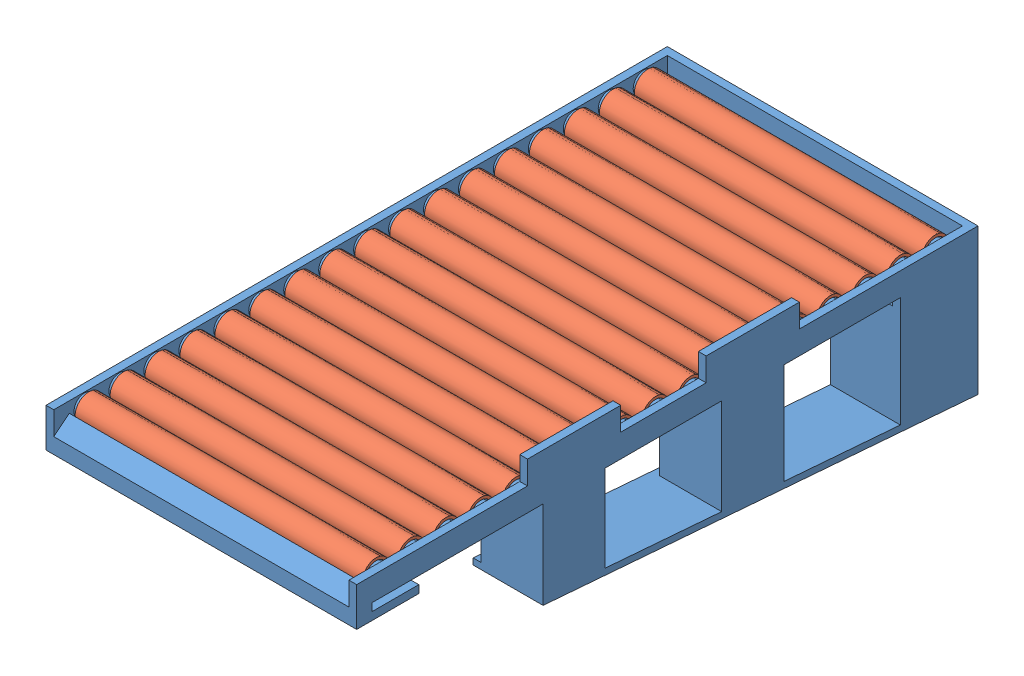
SolidWorks assembly LINE ASS, configuration Default. Lengths in mm.
Overall size (4000 2180 8000).
24 component instances, 4 part files, 54 mates.
Components (placement in the parent):
- LINE PRODUCTION-1: LINE PRODUCTION [Default] at origin size (4000 2180 8000)
- ROLLER-1: ROLLER [Default] at (0 150 3600) x (0 0.325893 0.945407) z (-1 0 0) size (350 350 3700)
- ROLLER-2: ROLLER [Default] at (0 150 3150) x (0 0 1) z (-1 0 0) size (350 350 3700)
- ROLLER-3: ROLLER [Default] at (0 150 2700) x (0 0 1) z (-1 0 0) size (350 350 3700)
- ROLLER-4: ROLLER [Default] at (0 150 2250) x (0 -0.864949 0.501859) z (-1 0 0) size (350 350 3700)
- ROLLER-5: ROLLER [Default] at (0 150 1800) x (0 0 1) z (-1 0 0) size (350 350 3700)
- ROLLER-6: ROLLER [Default] at (0 150 1350) x (0 0.030187 0.999544) z (-1 0 0) size (350 350 3700)
- ROLLER-7: ROLLER [Default] at (0 150 450) x (0 0.996582 0.082614) z (-1 0 0) size (350 350 3700)
- ROLLER-8: ROLLER [Default] at (0 150 0) x (0 0 1) z (-1 0 0) size (350 350 3700)
- ROLLER-9: ROLLER [Default] at (0 150 900) x (0 -0.361028 -0.932555) z (1 0 0) size (350 350 3700)
- ROLLER-10: ROLLER [Default] at (0 150 -450) x (0 -0.924225 -0.381849) z (1 0 0) size (350 350 3700)
- ROLLER-11: ROLLER [Default] at (0 150 -900) x (0 -0.924225 -0.381849) z (1 0 0) size (350 350 3700)
- ROLLER-13: ROLLER [Default] at (0 150 -1350) x (0 -0.924225 -0.381849) z (1 0 0) size (350 350 3700)
- ROLLER-14: ROLLER [Default] at (0 150 -1800) x (0 -0.924225 -0.381849) z (1 0 0) size (350 350 3700)
- ROLLER-15: ROLLER [Default] at (0 150 -2250) x (0 -0.924225 -0.381849) z (1 0 0) size (350 350 3700)
- ROLLER-16: ROLLER [Default] at (0 150 -2700) x (0 -0.924225 -0.381849) z (1 0 0) size (350 350 3700)
- ROLLER-17: ROLLER [Default] at (0 150 -3150) x (0 -0.650504 -0.759502) z (1 0 0) size (350 350 3700)
- ROLLER-18: ROLLER [Default] at (0 150 -3600) x (0 0.802662 -0.596435) z (1 0 0) size (350 350 3700)
- Support-1: Support [Default] at (1900 460 1466) x (0 0 1) z (-1 0 0) size (40 50 40)
- Support-2: Support [Default] at (1900 510 934) x (0 0 -1) z (-1 0 0) size (40 50 40)
- pusher-1: pusher [Default] at (1854 483.9666 1200) x (0 0 1) z (-1 0 0) size (600 100.08 85.42)
- pusher-2: pusher [Default] at (1854 477.8178 -1100) x (0 0 1) z (-1 0 0) size (600 100.08 85.42)
- Support-3: Support [Default] at (1900 471.1677 -1366) x (0 0 -1) z (-1 0 0) size (40 50 40)
- Support-4: Support [Default] at (1900 460 -834) x (0 0 1) z (-1 0 0) size (40 50 40)
Mates (geometry in assembly coordinates):
- Concentric1: concentric anti-aligned: cylinder of LINE PRODUCTION-1 through (2295.9798 150 3600) axis (-1 0 0) radius 140; cylinder of ROLLER-1 through (-1850 150 3600) axis (1 0 0) radius 141.5
- Coincident1: coincident anti-aligned: plane of ROLLER-1 through (0 150 3600) normal (-1 0 0); plane of assembly through (0 0 0) normal (1 0 0)
- Concentric3: concentric anti-aligned: cylinder of LINE PRODUCTION-1 through (2295.9798 150 3150) axis (-1 0 0) radius 140; cylinder of ROLLER-2 through (-1850 150 3150) axis (1 0 0) radius 175
- Coincident2: coincident anti-aligned: plane of ROLLER-2 through (0 150 3150) normal (-1 0 0); plane of assembly through (0 0 0) normal (1 0 0)
- Concentric4: concentric anti-aligned: cylinder of LINE PRODUCTION-1 through (2295.9798 150 2700) axis (-1 0 0) radius 140; cylinder of ROLLER-3 through (-1850 150 2700) axis (1 0 0) radius 175
- Coincident3: coincident anti-aligned: plane of ROLLER-3 through (0 150 2700) normal (-1 0 0); plane of assembly through (0 0 0) normal (1 0 0)
- Concentric5: concentric anti-aligned: cylinder of LINE PRODUCTION-1 through (2295.9798 150 2250) axis (-1 0 0) radius 140; cylinder of ROLLER-4 through (-1850 150 2250) axis (1 0 0) radius 175
- Coincident4: coincident anti-aligned: plane of ROLLER-4 through (0 150 2250) normal (-1 0 0); plane of assembly through (0 0 0) normal (1 0 0)
- Concentric6: concentric anti-aligned: cylinder of LINE PRODUCTION-1 through (2295.9798 150 1800) axis (-1 0 0) radius 140; cylinder of ROLLER-5 through (-1850 150 1800) axis (1 0 0) radius 175
- Concentric7: concentric anti-aligned: cylinder of LINE PRODUCTION-1 through (2295.9798 150 1350) axis (-1 0 0) radius 140; cylinder of ROLLER-6 through (-1850 150 1350) axis (1 0 0) radius 175
- Concentric8: concentric anti-aligned: cylinder of LINE PRODUCTION-1 through (2295.9798 150 450) axis (-1 0 0) radius 140; cylinder of ROLLER-7 through (-1850 150 450) axis (1 0 0) radius 175
- Concentric9: concentric anti-aligned: cylinder of LINE PRODUCTION-1 through (2295.9798 150 0) axis (-1 0 0) radius 140; cylinder of ROLLER-8 through (-1850 150 0) axis (1 0 0) radius 175
- Coincident5: coincident anti-aligned: plane of ROLLER-5 through (0 150 1800) normal (-1 0 0); plane of assembly through (0 0 0) normal (1 0 0)
- Coincident6: coincident anti-aligned: plane of ROLLER-6 through (0 150 1350) normal (-1 0 0); plane of assembly through (0 0 0) normal (1 0 0)
- Coincident7: coincident anti-aligned: plane of ROLLER-7 through (0 150 450) normal (-1 0 0); plane of assembly through (0 0 0) normal (1 0 0)
- Coincident8: coincident anti-aligned: plane of ROLLER-8 through (0 150 0) normal (-1 0 0); plane of assembly through (0 0 0) normal (1 0 0)
- Concentric101: concentric aligned: cylinder of LINE PRODUCTION-1 through (2295.9798 150 900) axis (-1 0 0) radius 140; cylinder of ROLLER-9 through (1850 150 900) axis (-1 0 0) radius 175
- Coincident9: coincident aligned: plane of ROLLER-9 through (0 150 900) normal (1 0 0); plane of assembly through (0 0 0) normal (1 0 0)
- Concentric111: concentric aligned: cylinder of LINE PRODUCTION-1 through (2295.9798 150 -450) axis (-1 0 0) radius 140; cylinder of ROLLER-10 through (1850 150 -450) axis (-1 0 0) radius 175
- Concentric121: concentric aligned: cylinder of LINE PRODUCTION-1 through (2295.9798 150 -900) axis (-1 0 0) radius 140; cylinder of ROLLER-11 through (1850 150 -900) axis (-1 0 0) radius 175
- Concentric131: concentric aligned: cylinder of LINE PRODUCTION-1 through (2295.9798 150 -1350) axis (-1 0 0) radius 140; cylinder of ROLLER-13 through (1850 150 -1350) axis (-1 0 0) radius 175
- Concentric141: concentric aligned: cylinder of LINE PRODUCTION-1 through (2295.9798 150 -1800) axis (-1 0 0) radius 140; cylinder of ROLLER-14 through (1850 150 -1800) axis (-1 0 0) radius 175
- Concentric151: concentric aligned: cylinder of LINE PRODUCTION-1 through (2295.9798 150 -2250) axis (-1 0 0) radius 140; cylinder of ROLLER-15 through (1850 150 -2250) axis (-1 0 0) radius 175
- Concentric161: concentric aligned: cylinder of LINE PRODUCTION-1 through (2295.9798 150 -2700) axis (-1 0 0) radius 140; cylinder of ROLLER-16 through (1850 150 -2700) axis (-1 0 0) radius 175
- Concentric171: concentric aligned: cylinder of LINE PRODUCTION-1 through (2295.9798 150 -3150) axis (-1 0 0) radius 140; cylinder of ROLLER-17 through (1850 150 -3150) axis (-1 0 0) radius 175
- Concentric181: concentric aligned: cylinder of LINE PRODUCTION-1 through (2295.9798 150 -3600) axis (-1 0 0) radius 140; cylinder of ROLLER-18 through (1850 150 -3600) axis (-1 0 0) radius 175
- Coincident10: coincident aligned: plane of ROLLER-10 through (0 150 -450) normal (1 0 0); plane of assembly through (0 0 0) normal (1 0 0)
- Coincident11: coincident aligned: plane of ROLLER-11 through (0 150 -900) normal (1 0 0); plane of assembly through (0 0 0) normal (1 0 0)
- Coincident12: coincident aligned: plane of ROLLER-14 through (0 150 -1800) normal (1 0 0); plane of assembly through (0 0 0) normal (1 0 0)
- Coincident13: coincident aligned: plane of ROLLER-13 through (0 150 -1350) normal (1 0 0); plane of assembly through (0 0 0) normal (1 0 0)
- Coincident14: coincident aligned: plane of ROLLER-15 through (0 150 -2250) normal (1 0 0); plane of assembly through (0 0 0) normal (1 0 0)
- Coincident15: coincident aligned: plane of ROLLER-16 through (0 150 -2700) normal (1 0 0); plane of assembly through (0 0 0) normal (1 0 0)
- Coincident16: coincident aligned: plane of ROLLER-17 through (0 150 -3150) normal (1 0 0); plane of assembly through (0 0 0) normal (1 0 0)
- Coincident17: coincident aligned: plane of ROLLER-18 through (0 150 -3600) normal (1 0 0); plane of assembly through (0 0 0) normal (1 0 0)
- Coincident18: coincident anti-aligned: plane of LINE PRODUCTION-1 through (1900 300 3900) normal (-1 0 0); plane of Support-1 through (1900 510 1466) normal (1 0 0)
- Distance2: distance = 300 mm anti-aligned: plane of LINE PRODUCTION-1 through (663.0683 600 1800) normal (0 0 1); plane of Support-1 through (1894 510 1500) normal (0 0 -1)
- Distance3: distance = 90 mm aligned: plane of LINE PRODUCTION-1 through (663.0683 600 600) normal (0 1 0); plane of Support-1 through (1900 510 1466) normal (0 1 0)
- Coincident23: coincident anti-aligned: plane of LINE PRODUCTION-1 through (1900 300 3900) normal (-1 0 0); plane of Support-2 through (1900 460 934) normal (1 0 0)
- Distance4: distance = 300 mm anti-aligned: plane of Support-2 through (1894 460 900) normal (0 0 1); plane of LINE PRODUCTION-1 through (663.0683 300 600) normal (0 0 -1)
- Distance6: distance = 90 mm aligned: plane of LINE PRODUCTION-1 through (663.0683 600 600) normal (0 1 0); plane of Support-2 through (1900 510 934) normal (0 1 0)
- Concentric182: concentric anti-aligned: cylinder of Support-2 through (1882 472 944) axis (0 0 -1) radius 4; circle of ?
- Coincident28: coincident anti-aligned: plane of Support-2 through (1894 460 900) normal (0 0 1); plane of ? through (1859.035 498.4123 900) normal (0 0 -1)
- Coincident29: coincident anti-aligned: circle of ?; circle of ?
- Coincident31: coincident anti-aligned: plane of pusher-1 through (1722.9976 463.4725 905) normal (0 0 -1); plane of ? through (1801.7579 531.7296 905) normal (0 0 1)
- Concentric184: concentric anti-aligned: circle of pusher-1; circle of ?
- Coincident36: coincident anti-aligned: plane of Support-2 through (1894 460 900) normal (0 0 1); plane of pusher-1 through (1844 433.9666 900) normal (0 0 -1)
- Coincident37: coincident anti-aligned: plane of Support-2 through (1894 460 934) normal (-1 0 0); plane of pusher-1 through (1894 533.9666 910) normal (1 0 0)
- Coincident38: coincident anti-aligned: plane of LINE PRODUCTION-1 through (1900 300 3900) normal (-1 0 0); plane of Support-4 through (1900 510 -834) normal (1 0 0)
- Distance7: distance = 300 mm anti-aligned: plane of Support-4 through (1894 510 -800) normal (0 0 -1); plane of LINE PRODUCTION-1 through (663.0683 300 -500) normal (0 0 1)
- Distance8: distance = 90 mm aligned: plane of Support-4 through (1900 510 -834) normal (0 1 0); plane of LINE PRODUCTION-1 through (663.0683 600 -500) normal (0 1 0)
- Coincident41: coincident anti-aligned: plane of LINE PRODUCTION-1 through (1900 300 3900) normal (-1 0 0); plane of Support-3 through (1900 421.1677 -1366) normal (1 0 0)
- Distance10: distance = 300 mm anti-aligned: plane of Support-3 through (1894 421.1677 -1400) normal (0 0 1); plane of LINE PRODUCTION-1 through (663.0683 600 -1700) normal (0 0 -1)
- Coincident44: coincident anti-aligned: plane of pusher-2 through (1844 427.8178 -1400) normal (0 0 -1); plane of Support-3 through (1894 421.1677 -1400) normal (0 0 1)
- Coincident45: coincident anti-aligned: plane of pusher-2 through (1894 527.8178 -810) normal (1 0 0); plane of Support-4 through (1894 510 -834) normal (-1 0 0)
